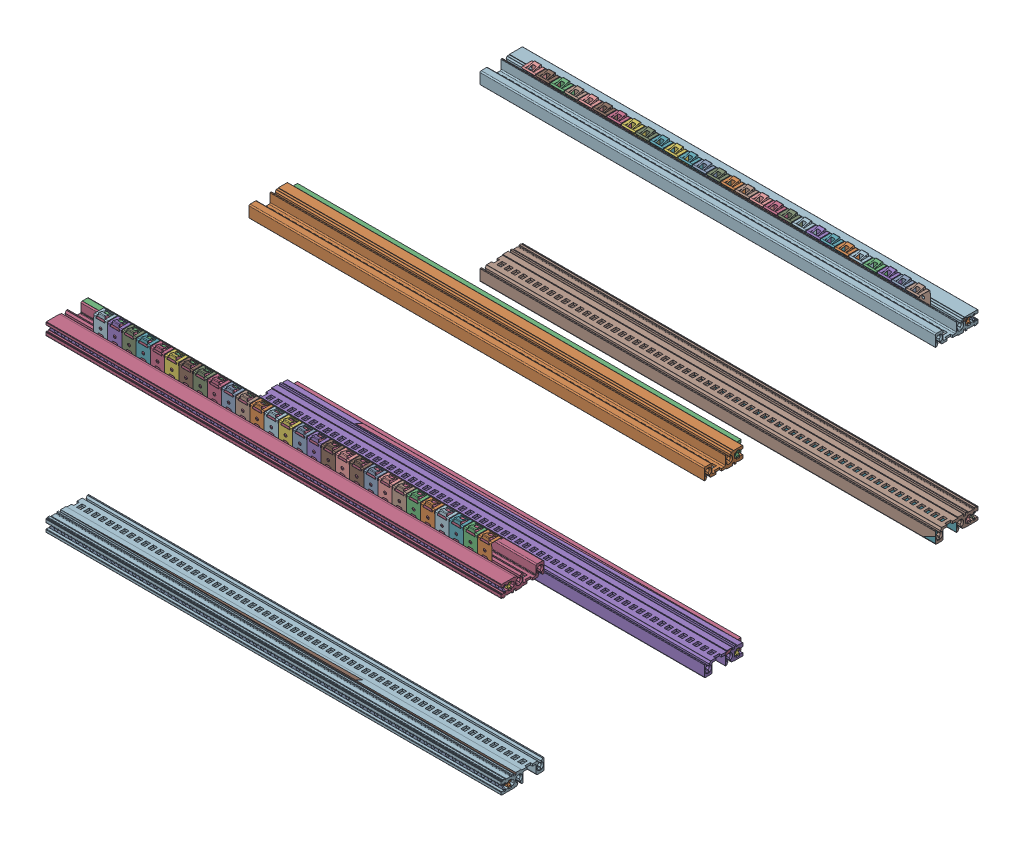
SolidWorks assembly MSAusbau-propacPro-63TE, configuration По умолчанию. Lengths in mm.
Overall size (325.12 150.38 340.5).
38 component instances, 8 part files, 0 mates.
Components (placement in the parent):
- MS-HI-STH063TE-----1: MS-HI-STH063TE---- [По умолчанию] at (0 113.55 -135) x (1 0 0) z (0 0 -1) size (325.12 9 27.5)
  - MS-HI-STH063TE-----1: MS-HI-STH063TE---- [По умолчанию] at origin size (325.12 9 27.5)
  - MS-HI-STH063TE----_2-1: MS-HI-STH063TE----_2 [По умолчанию] at origin size (325.12 9 27.5)
  - GS---M25-063TE-----1: GS---M25-063TE---- [По умолчанию] at origin size (324.62 5 2)
- MS-HI-STH063TE-----2: MS-HI-STH063TE---- [По умолчанию] at (0 0 -135) x (-1 0 0) z (0 0 -1) size (325.12 9 27.5)
  - MS-HI-STH063TE-----1: MS-HI-STH063TE---- [По умолчанию] at origin size (325.12 9 27.5)
  - MS-HI-STH063TE----_2-1: MS-HI-STH063TE----_2 [По умолчанию] at origin size (325.12 9 27.5)
  - GS---M25-063TE-----1: GS---M25-063TE---- [По умолчанию] at origin size (324.62 5 2)
- MS-HI-VTH063TE-EMC-1: MS-HI-VTH063TE-EMC [По умолчанию] at (0 113.55 -300) x (1 0 0) z (0 0 -1) size (325.12 19.02 30.5)
  - KONTAKTSTR-MS-ADBL-283.98-1: KONTAKTSTR-MS-ADBL-283.98 [По умолчанию] at origin size (285.5 16.81 12.07)
  - MS-HI-VTH063TE-----1: MS-HI-VTH063TE---- [По умолчанию] at origin size (325.12 9 30.5)
    - MS-HI-VTH063TE-----1: MS-HI-VTH063TE---- [По умолчанию] at origin size (325.12 9 30.5)
    - MS-HI-VTH063TE----_2-1: MS-HI-VTH063TE----_2 [По умолчанию] at origin size (325.12 9 30.5)
    - LS-------063TE-----1: LS-------063TE---- [По умолчанию] at origin size (324.92 5 1)
    - GS---M25-063TE-----1: GS---M25-063TE---- [По умолчанию] at origin size (324.62 5 2)
- MS-HI-VTH063TE-EMC-2: MS-HI-VTH063TE-EMC [По умолчанию] at (0 0 -300) x (-1 0 0) z (0 0 -1) size (325.12 19.02 30.5)
  - KONTAKTSTR-MS-ADBL-283.98-1: KONTAKTSTR-MS-ADBL-283.98 [По умолчанию] at origin size (285.5 16.81 12.07)
  - MS-HI-VTH063TE-----1: MS-HI-VTH063TE---- [По умолчанию] at origin size (325.12 9 30.5)
    - MS-HI-VTH063TE-----1: MS-HI-VTH063TE---- [По умолчанию] at origin size (325.12 9 30.5)
    - MS-HI-VTH063TE----_2-1: MS-HI-VTH063TE----_2 [По умолчанию] at origin size (325.12 9 30.5)
    - LS-------063TE-----1: LS-------063TE---- [По умолчанию] at origin size (324.92 5 1)
    - GS---M25-063TE-----1: GS---M25-063TE---- [По умолчанию] at origin size (324.62 5 2)
- MS-HI-VTH063TE-EMC-3: MS-HI-VTH063TE-EMC [По умолчанию] at (0 113.55 0) x (-1 0 0) z (0 0 1) size (325.12 19.02 30.5)
  - KONTAKTSTR-MS-ADBL-283.98-1: KONTAKTSTR-MS-ADBL-283.98 [По умолчанию] at origin size (285.5 16.81 12.07)
  - MS-HI-VTH063TE-----1: MS-HI-VTH063TE---- [По умолчанию] at origin size (325.12 9 30.5)
    - MS-HI-VTH063TE-----1: MS-HI-VTH063TE---- [По умолчанию] at origin size (325.12 9 30.5)
    - MS-HI-VTH063TE----_2-1: MS-HI-VTH063TE----_2 [По умолчанию] at origin size (325.12 9 30.5)
    - LS-------063TE-----1: LS-------063TE---- [По умолчанию] at origin size (324.92 5 1)
    - GS---M25-063TE-----1: GS---M25-063TE---- [По умолчанию] at origin size (324.62 5 2)
- MS-HI-VTH063TE-EMC-4: MS-HI-VTH063TE-EMC [По умолчанию] at origin size (325.12 19.02 30.5)
  - KONTAKTSTR-MS-ADBL-283.98-1: KONTAKTSTR-MS-ADBL-283.98 [По умолчанию] at origin size (285.5 16.81 12.07)
  - MS-HI-VTH063TE-----1: MS-HI-VTH063TE---- [По умолчанию] at origin size (325.12 9 30.5)
    - MS-HI-VTH063TE-----1: MS-HI-VTH063TE---- [По умолчанию] at origin size (325.12 9 30.5)
    - MS-HI-VTH063TE----_2-1: MS-HI-VTH063TE----_2 [По умолчанию] at origin size (325.12 9 30.5)
    - LS-------063TE-----1: LS-------063TE---- [По умолчанию] at origin size (324.92 5 1)
    - GS---M25-063TE-----1: GS---M25-063TE---- [По умолчанию] at origin size (324.62 5 2)
- IS-35-35-062TE-----1: IS-35-35-062TE---- [По умолчанию] at (0 113.55 -135) x (1 0 0) z (0 0 -1) size (316.88 7.8 3.8)
- IS-35-35-062TE-----2: IS-35-35-062TE---- [По умолчанию] at (0 0 -135) x (-1 0 0) z (0 0 -1) size (316.88 7.8 3.8)
